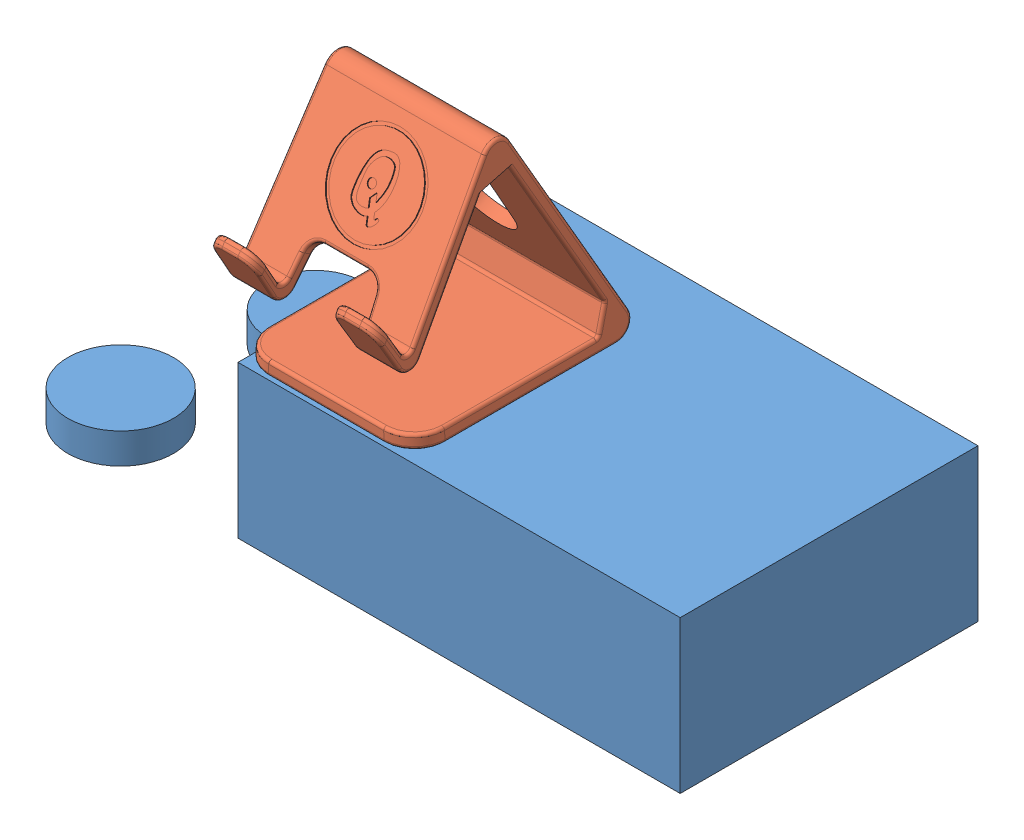
SolidWorks assembly 装配体1.1_2, configuration Default. Lengths in mm.
Overall size (214.49 126.04 109.37).
3 component instances, 3 part files, 3 mates.
Components (placement in the parent):
- 零件1^装配体1.1_2-1: 零件1^装配体1.1_2 [默认] x (0 0 -1) z (1 0 0) (virtual)
- 零件1.1_2-1: 零件1.1_2 [默认] at (-31.9667 -200.5504 122.8033) size (214.49 50 101.62)
- 3D打印手机支架-1: 3D打印手机支架 [默认] at (-75.5869 -149.5504 171.6818) size (57.92 76.04 83.06)
Mates (geometry in assembly coordinates):
- 重合29: coincident anti-aligned: plane of 零件1.1_2-1 through (-31.9667 -150.5504 122.8033) normal (0 1 0); plane of 3D打印手机支架-1 through (-94.5799 -150.5504 161.6818) normal (0 -1 0)
- 重合30: coincident aligned: plane of 零件1.1_2-1 through (-104.548 -150.5504 171.6818) normal (0 0 1); plane of 3D打印手机支架-1 through (-46.5869 -145.0504 171.6818) normal (0 0 1)
- 重合32: coincident: plane of 零件1.1_2-1 through (-104.548 -150.5504 171.6818) normal (-1 0 0); line of 3D打印手机支架-1 through (-104.548 -148.5129 105.231) axis (0 0 1)
